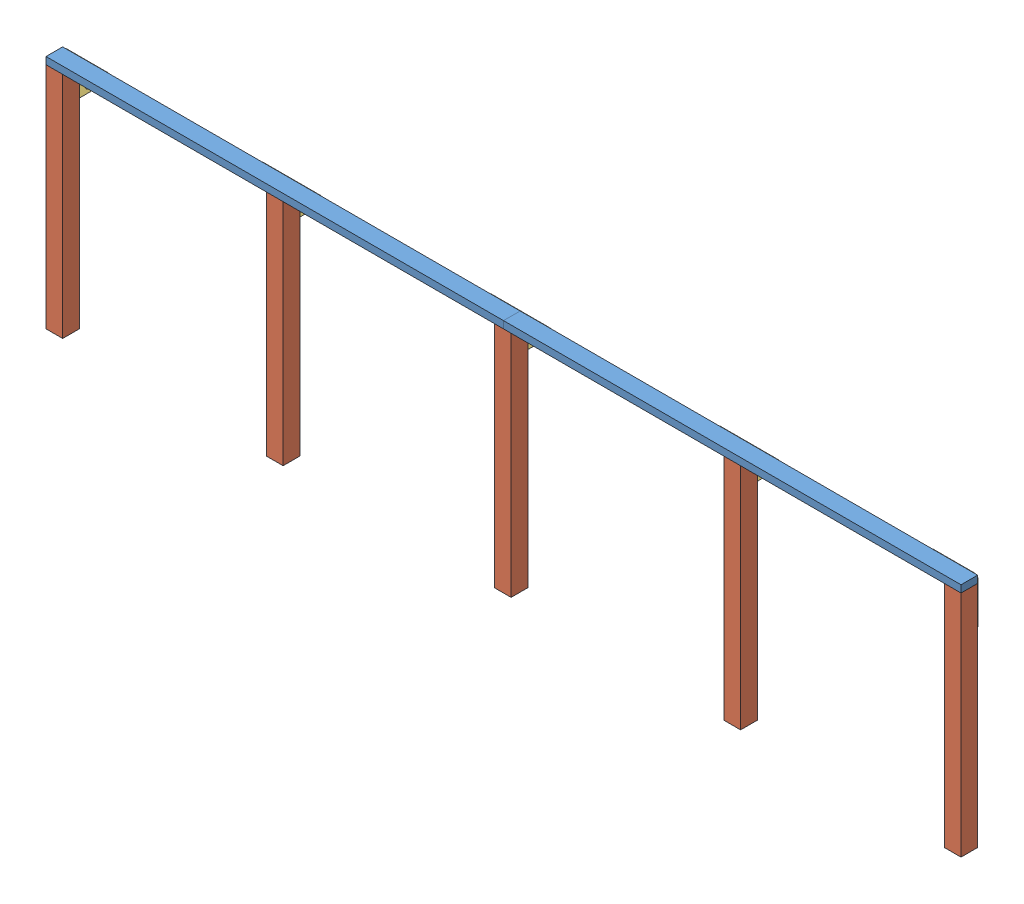
SolidWorks assembly stringer_4ft, configuration Default. Lengths in mm.
Overall size (5108.48 1373.14 90.54).
12 component instances, 3 part files, 14 mates.
Components (placement in the parent):
- 2x4x8ft-1: 2x4x8ft [Default] at (1734.6857 1575.9512 1842.2859) size (2438.4 38.1 88.9)
- 2x4x8ft-2: 2x4x8ft [Default] at (4173.0857 1575.9512 1842.2859) size (2438.4 38.1 88.9)
- 4x4x4ft-1: 4x4x4ft [Default] at (-614.8143 1537.8512 1842.2859) size (88.9 1219.2 88.9)
- 4x4x4ft-2: 4x4x4ft [Default] at (4173.0857 1537.8512 1842.2859) size (88.9 1219.2 88.9)
- 4x4x4ft-3: 4x4x4ft [Default] at (559.9357 1537.8512 1842.2859) size (88.9 1219.2 88.9)
- 4x4x4ft-4: 4x4x4ft [Default] at (1775.1299 1537.8512 1842.2859) size (88.9 1219.2 88.9)
- 4x4x4ft-5: 4x4x4ft [Default] at (2998.3357 1537.8512 1842.2859) size (88.9 1219.2 88.9)
- bracket-1: bracket [Default] at (1933.4802 1575.9512 1840.6441) size (343.43 190.77 1.64)
- bracket-2: bracket [Default] at (3152.6802 1575.9512 1840.6441) size (343.43 190.77 1.64)
- bracket-4: bracket [Default] at (-703.7143 1295.0105 1840.6441) x (-0.707107 -0.707107 0) z (0 0 1) size (343.43 190.77 1.64)
- bracket-5: bracket [Default] at (3892.145 1575.9512 1840.6441) x (-0.707107 0.707107 0) z (0 0 1) size (343.43 190.77 1.64)
- bracket-6: bracket [Default] at (714.2802 1575.9512 1840.6441) size (343.43 190.77 1.64)
Mates (geometry in assembly coordinates):
- Coincident4: coincident: point of 2x4x8ft-1; point of 2x4x8ft-2
- Coincident6: coincident: point of 2x4x8ft-1; point of 4x4x4ft-1
- Coincident7: coincident: point of 2x4x8ft-2; point of 4x4x4ft-2
- Coincident8: coincident: line of 4x4x4ft-3 through (559.9357 1537.8512 1931.1859) axis (0 0 -1)
- Coincident9: coincident aligned: line of 2x4x8ft-1 through (-703.7143 1537.8512 1931.1859) axis (1 0 0); line of 4x4x4ft-3 through (471.0357 1537.8512 1931.1859) axis (1 0 0)
- Coincident12: coincident: point of 2x4x8ft-1; line of 4x4x4ft-4 through (1686.2299 1537.8512 1931.1859) axis (1 0 0)
- Coincident17: coincident: unknown of 2x4x8ft-1; moEndPointRef_w of bracket-1
- Coincident19: coincident: line of assembly; line of 4x4x4ft-5 through (2909.4357 1537.8512 1842.2859) axis (0 0 1); point of assembly
- Coincident20: coincident: unknown of 2x4x8ft-2; unknown of bracket-2
- Coincident35: coincident anti-aligned: line of 4x4x4ft-1 through (-703.7143 318.6512 1842.2859) axis (0 1 0); line of bracket-4 through (-703.7143 1556.9012 1842.2859) axis (0 -1 0)
- Coincident36: coincident anti-aligned: line of 2x4x8ft-1 through (1734.6857 1575.9512 1842.2859) axis (-1 0 0); line of bracket-4 through (-684.6643 1575.9512 1842.2859) axis (1 0 0)
- Coincident37: coincident aligned: line of 2x4x8ft-2 through (4173.0857 1575.9512 1842.2859) axis (-1 0 0); line of bracket-5 through (4154.0357 1575.9512 1842.2859) axis (-1 0 0)
- Coincident38: coincident anti-aligned: line of 4x4x4ft-2 through (4173.0857 318.6512 1842.2859) axis (0 1 0); line of bracket-5 through (4173.0857 1556.9012 1842.2859) axis (0 -1 0)
- Coincident50: coincident: unknown of bracket-6
